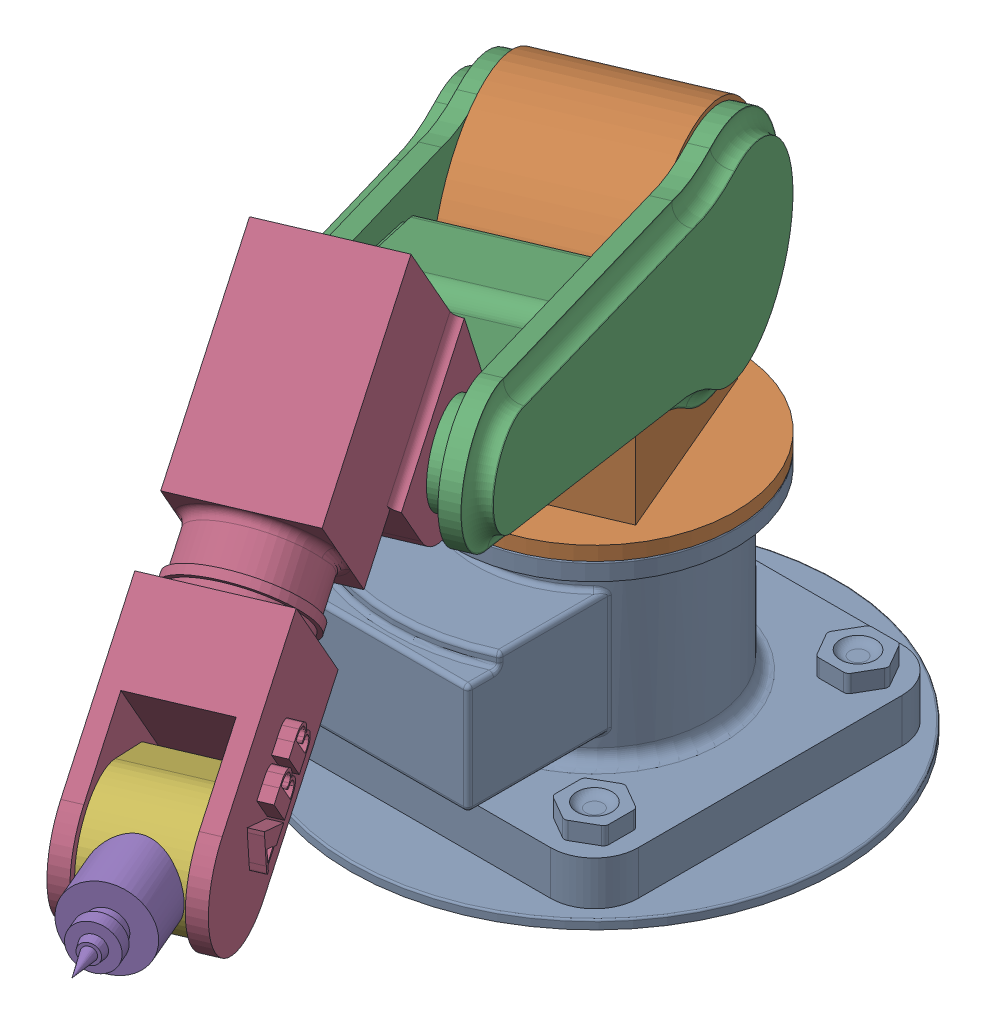
SolidWorks assembly Assem2, configuration Default. Lengths in mm.
Overall size (746.76 843.25 1314.99).
5 component instances, 5 part files, 8 mates.
Components (placement in the parent):
- Part1-1: Part1 [Default] at (264.8684 33.4285 256.7086) size (555 280 555)
- Part2-1: Part2 [Default] at (264.8684 193.4285 256.7086) x (0.392324 0 0.919827) z (-0.919827 0 0.392324) size (320 466 320)
- Part3-1: Part3 [Default] at (264.8684 529.4285 256.7086) x (-0.090762 0.972872 -0.212797) z (-0.381681 -0.231345 -0.894874) size (250 260.07 700)
- Part4-1: Part4 [Default] at (451.8039 816.7954 720.4794) x (0.31325 -0.602065 0.734433) z (-0.919827 0 0.392324) size (585 297.71 165)
- Part5-1: Part5 [Default] at (611.5614 509.7421 1095.0403) x (0.392322 0.002912 0.919823) z (-0.919827 0 0.392324) size (275 130 100)
Mates (geometry in assembly coordinates):
- Concentric1: concentric anti-aligned: cylinder of Part1-1 through (264.8684 113.4285 256.7086) axis (0 1 0) radius 100; cylinder of Part2-1 through (264.8684 313.4285 256.7086) axis (0 -1 0) radius 100
- Coincident1: coincident aligned: plane of Part1-1 through (264.8684 313.4285 256.7086) normal (0 1 0); circle of Part2-1
- Concentric4: concentric anti-aligned: cylinder of Part2-1 through (182.0839 529.4285 292.0178) axis (0.919827 0 -0.392324) radius 75; cylinder of Part3-1 through (347.6528 529.4285 221.3995) axis (-0.919827 0 0.392324) radius 75
- Coincident2: coincident anti-aligned: plane of Part2-1 through (182.0839 529.4285 292.0178) normal (-0.919827 0 0.392324); plane of Part3-1 through (372.9244 645.1008 739.4547) normal (0.919827 0 -0.392324)
- Concentric5: concentric anti-aligned: cylinder of Part3-1 through (538.4933 645.1008 668.8364) axis (-0.919827 0 0.392324) radius 50; cylinder of Part4-1 through (372.9244 645.1008 739.4547) axis (0.919827 0 -0.392324) radius 50
- Coincident3: coincident anti-aligned: plane of Part3-1 through (372.9244 645.1008 739.4547) normal (0.919827 0 -0.392324); plane of Part4-1 through (372.9244 645.1008 739.4547) normal (-0.919827 0 0.392324)
- Concentric6: concentric aligned: cylinder of Part4-1 through (565.57 509.7421 1114.6565) axis (0.919827 0 -0.392324) radius 50; cylinder of Part5-1 through (565.57 509.7421 1114.6565) axis (0.919827 0 -0.392324) radius 50
- Coincident4: coincident anti-aligned: plane of Part4-1 through (657.5527 509.7421 1075.4241) normal (-0.919827 0 0.392324); plane of Part5-1 through (657.5527 509.7421 1075.4241) normal (0.919827 0 -0.392324)
